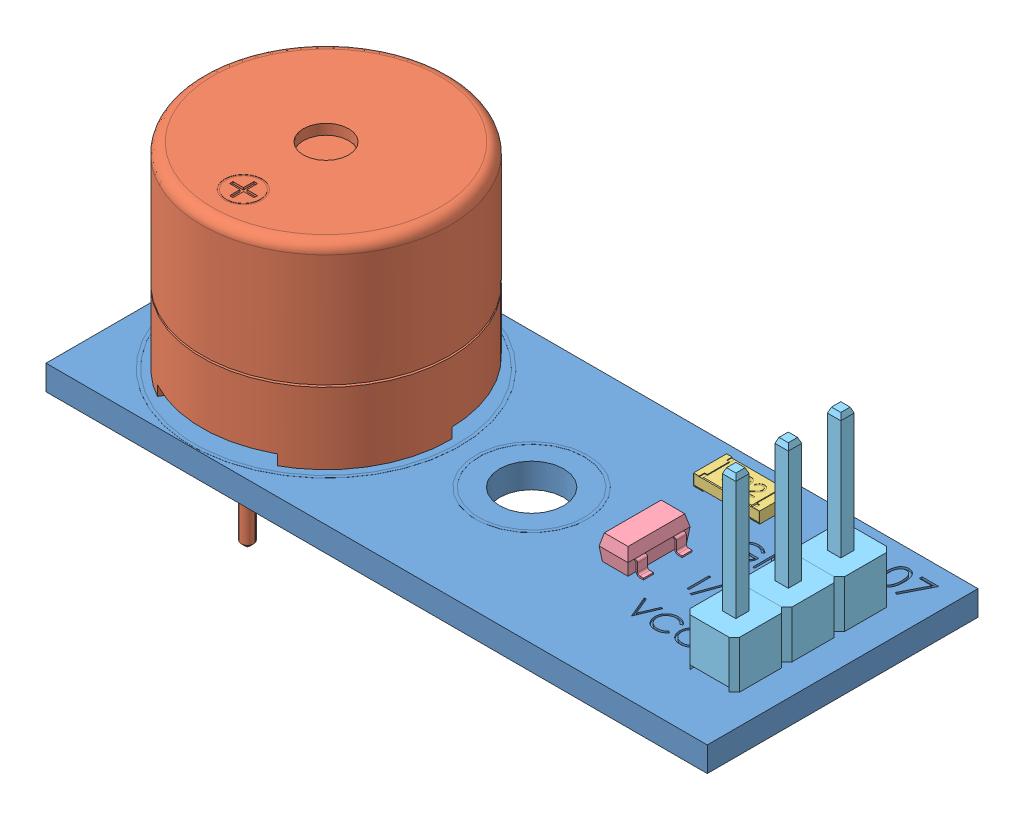
SolidWorks assembly Buzzer Module - FC-07, configuration Default. Lengths in mm.
Overall size (32 15 13.1).
8 component instances, 5 part files, 12 mates.
Components (placement in the parent):
- Buzzer Module - FC-07 - PCB-1: Buzzer Module - FC-07 - PCB [Default] at origin size (32 1.2 13.1)
- Buzzer - 7.6mm-1: Buzzer - 7.6mm [Default] at (-9 1.2 0) x (-1 0 0) z (0 1 0) size (12 12 15)
- Resistor - SMD - 1206-1: Resistor - SMD - 1206 [Resistor - SMD - 1206 - 1K] at (6.4157 1.2 -4.7683) x (1 0 0) z (0 1 0) size (3.2 1.6 0.55)
- Transistör - SMD - BC817 NPN - SOT23-1: Transistör - SMD - BC817 NPN - SOT23 [Predeterminado] at (6.4157 1.8726 0) x (0 0 -1) z (0 1 0) size (3 2.25 1.22)
- 3x_Male_Pin_2.54_mm.STEP-1: 3x_Male_Pin_2.54_mm.STEP [Default] at (1.9813 -4.0562 1.6613) x (0 0 -1) z (1 0 0) size (7.62 11.1 2.4)
  - 1_Male_Pin_2.54_mm.STEP-1: 1_Male_Pin_2.54_mm.STEP [Default] at (3.8763 2.2562 11.0637) size (2.54 11.1 2.4)
  - 1_Male_Pin_2.54_mm.STEP-2: 1_Male_Pin_2.54_mm.STEP [Default] at (1.3363 2.2562 11.0637) size (2.54 11.1 2.4)
  - 1_Male_Pin_2.54_mm.STEP-3: 1_Male_Pin_2.54_mm.STEP [Default] at (-1.2037 2.2562 11.0637) size (2.54 11.1 2.4)
Mates (geometry in assembly coordinates):
- Coincident2: coincident anti-aligned: plane of Buzzer Module - FC-07 - PCB-1 through (0 1.2 0) normal (0 1 0); plane of Resistor - SMD - 1206-1 through (6.4157 1.2 -4.7683) normal (0 -1 0)
- Coincident4: coincident anti-aligned: plane of Buzzer Module - FC-07 - PCB-1 through (0 1.2 0) normal (0 1 0); plane of Transistör - SMD - BC817 NPN - SOT23-1 through (5.4746 1.2 -1.512) normal (0 -1 0)
- Width1: width aligned: plane of Buzzer Module - FC-07 - PCB-1 through (-16 1.2 6.55) normal (0 0 1); plane of Transistör - SMD - BC817 NPN - SOT23-1 through (-16 1.2 -6.55) normal (0 0 -1); plane of Buzzer Module - FC-07 - PCB-1 through (5.29 1.1826 0.2418) normal (0 0 1); plane of Transistör - SMD - BC817 NPN - SOT23-1 through (5.8427 1.1826 -0.2418) normal (0 0 -1)
- Distance1: distance = 1 mm aligned: plane of Resistor - SMD - 1206-1 through (6.4157 1.2 -5.55) normal (0 0 -1); plane of Buzzer Module - FC-07 - PCB-1 through (-16 1.2 -6.55) normal (0 0 -1)
- Distance2: distance = 2.79 mm: plane of Transistör - SMD - BC817 NPN - SOT23-1 through (5.29 1.1826 -0.2418) normal (-1 0 0); cylinder of Buzzer Module - FC-07 - PCB-1 through (0.95 -0.001 0) axis (0 1 0) radius 1.55
- Width2: width anti-aligned: plane of Resistor - SMD - 1206-1 through (4.8157 1.2 -4.7683) normal (-1 0 0); plane of Transistör - SMD - BC817 NPN - SOT23-1 through (8.0157 1.2 -4.7683) normal (1 0 0); plane of Resistor - SMD - 1206-1 through (7.5415 1.1826 -0.6945) normal (1 0 0); plane of Transistör - SMD - BC817 NPN - SOT23-1 through (5.29 1.1826 -0.2418) normal (-1 0 0)
- Concentric4: concentric anti-aligned: cylinder of Buzzer Module - FC-07 - PCB-1 through (-9 -0.001 3.8) axis (0 1 0) radius 0.4; cylinder of Buzzer - 7.6mm-1 through (-9 1.7 3.8) axis (0 -1 0) radius 0.3
- Concentric5: concentric anti-aligned: cylinder of Buzzer Module - FC-07 - PCB-1 through (-9 -0.001 -3.8) axis (0 1 0) radius 0.4; cylinder of Buzzer - 7.6mm-1 through (-9 1.7 -3.8) axis (0 -1 0) radius 0.3
- Coincident6: coincident anti-aligned: plane of Buzzer Module - FC-07 - PCB-1 through (0 1.2 0) normal (0 1 0); plane of Buzzer - 7.6mm-1 through (-9 1.2 0) normal (0 -1 0)
- Concentric6: concentric anti-aligned: cylinder of Buzzer Module - FC-07 - PCB-1 through (13.37 -0.001 2.54) axis (0 1 0) radius 0.4; circle of 3x_Male_Pin_2.54_mm.STEP-1
- Parallel1: parallel aligned: plane of Buzzer Module - FC-07 - PCB-1 through (16 1.2 -6.55) normal (1 0 0); plane of 3x_Male_Pin_2.54_mm.STEP-1/1_Male_Pin_2.54_mm.STEP-1 through (14.57 3.5 -3.81) normal (1 0 0)
- Coincident8: coincident anti-aligned: plane of Buzzer Module - FC-07 - PCB-1 through (0 1.2 0) normal (0 1 0); plane of 3x_Male_Pin_2.54_mm.STEP-1/1_Male_Pin_2.54_mm.STEP-3 through (13.045 1.2 2.865) normal (0 -1 0)
